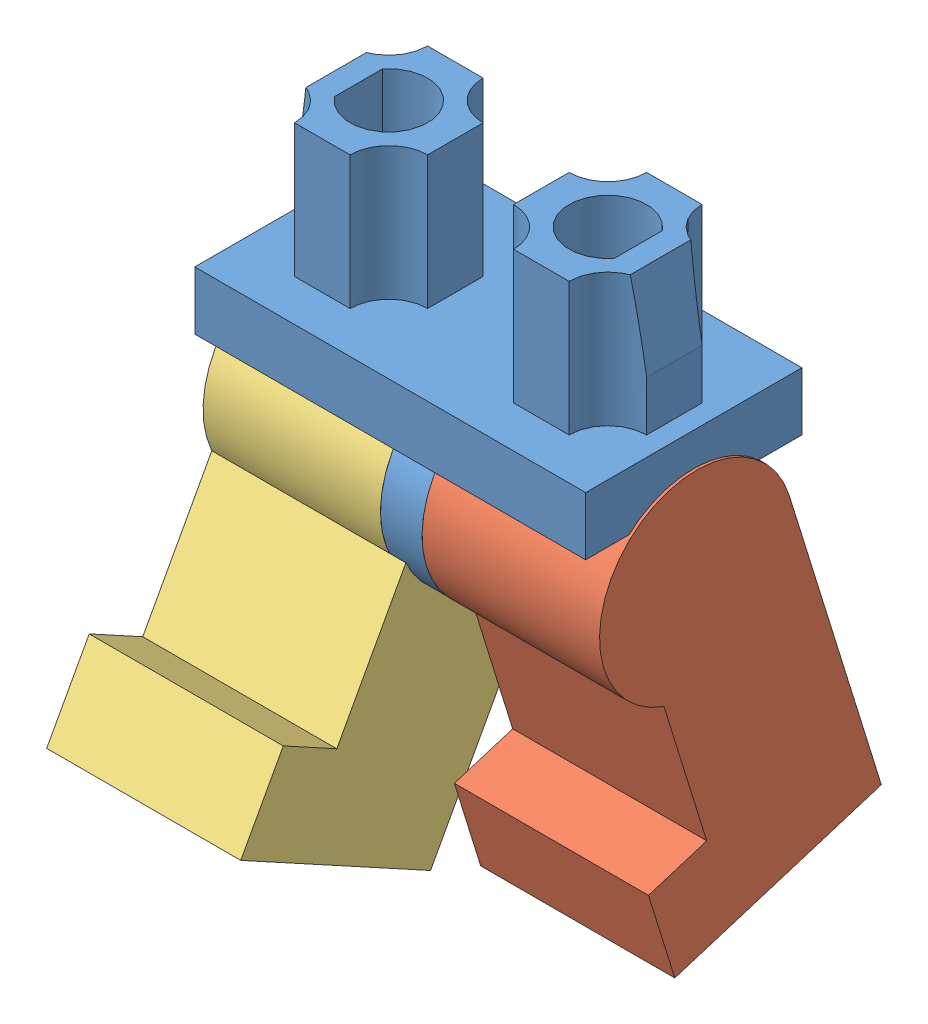
SolidWorks assembly Practice Model - Lego Legs & hips, configuration Default. Lengths in mm.
Overall size (14.3 21.47 15.81).
3 component instances, 3 part files, 6 mates.
Components (placement in the parent):
- Practice Model -Lego Hips in progress.-1: Practice Model -Lego Hips in progress. [Default] at origin size (14.1 13 7.8)
- Practice Model - Lego Leg (Left)-1: Practice Model - Lego Leg (Left) [Default] at (7.15 -4.7 0) x (1 0 0) z (0 -0.296591 0.955004) size (7 14.7 7.8)
- MirrorPractice Model - Lego Leg (Left)-2: MirrorPractice Model - Lego Leg (Left) [Default] at (-7.15 -4.7 0) x (-1 0 0) z (0 -0.479261 -0.877673) size (7 14.7 7.8)
Mates (geometry in assembly coordinates):
- Concentric1: concentric aligned: cylinder of Practice Model -Lego Hips in progress.-1 through (3.15 -4.7 0) axis (-1 0 0) radius 1.2; cylinder of Practice Model - Lego Leg (Left)-1 through (7.151 -4.7 0) axis (-1 0 0) radius 1.125
- Coincident1: coincident anti-aligned: plane of Practice Model -Lego Hips in progress.-1 through (0.75 0 0) normal (1 0 0); plane of Practice Model - Lego Leg (Left)-1 through (0.75 -4.7 0) normal (-1 0 0)
- Concentric2: concentric aligned: cylinder of Practice Model -Lego Hips in progress.-1 through (-3.15 -4.7 0) axis (1 0 0) radius 1.2; cylinder of MirrorPractice Model - Lego Leg (Left)-2 through (-7.151 -4.7 0) axis (1 0 0) radius 1.125
- Coincident2: coincident anti-aligned: plane of Practice Model -Lego Hips in progress.-1 through (-0.75 0 0) normal (-1 0 0); plane of MirrorPractice Model - Lego Leg (Left)-2 through (-0.75 -4.7 0) normal (1 0 0)
- LimitAngle1: limit planar angle = 0.301121 rad aligned: plane of Practice Model - Lego Leg (Left)-1 through (0.15 -5.3228 2.0055) normal (0 -0.296591 0.955004); plane of Practice Model -Lego Hips in progress.-1 through (7.05 0 3.9) normal (0 0 1)
- LimitAngle2: limit planar angle = 0.499812 rad aligned: plane of MirrorPractice Model - Lego Leg (Left)-2 through (-0.15 -3.6936 1.8431) normal (0 0.479261 0.877673); plane of Practice Model -Lego Hips in progress.-1 through (7.05 0 3.9) normal (0 0 1)
